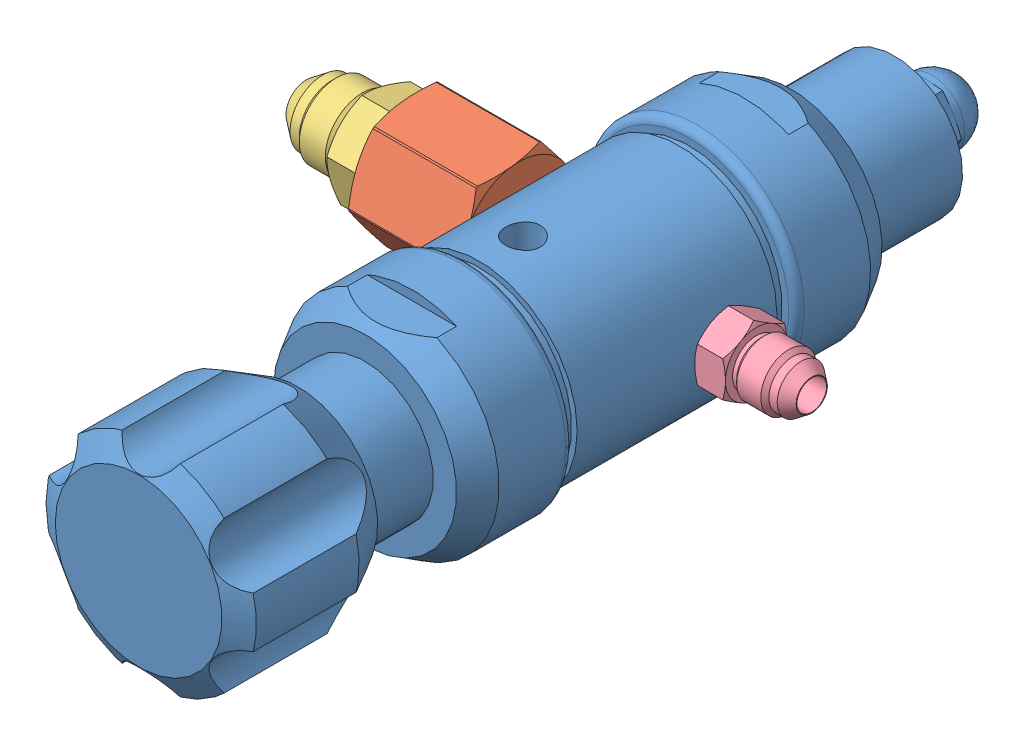
SolidWorks assembly PRV-3 Assembly, configuration Default. Lengths in mm.
Overall size (139.78 55.88 212.09).
4 component instances, 4 part files, 5 mates.
Components (placement in the parent):
- KCY1JPA412A20000_PRT_29-1: KCY1JPA412A20000_PRT_29 [Default] at origin size (56.39 55.88 212.09)
- 51205K317_EXTREME-PRESSURE 316 SS THREADED PIPE FITTING-1: 51205K317_EXTREME-PRESSURE 316 SS THREADED PIPE FITTING [51205K317] at (-34.807 0 86.614) x (-1 0 0) z (0 0.601506 -0.798868) size (44.05 32.74 28.57)
- 0500_OD_JIC_to_0500_NPT-1: 0500_OD_JIC_to_0500_NPT [50715K802] at (-59.826 0 86.614) x (-1 0 0) z (0 -0.969103 0.246658) size (55.21 25.66 22.23)
- 50715K163_TYPE 316 SS 37 DEGREE FLARED TUBE FITTING-1: 50715K163_TYPE 316 SS 37 DEGREE FLARED TUBE FITTING [50715K163] at (29.187 0 86.614) size (36.32 18.33 15.88)
Mates (geometry in assembly coordinates):
- Concentric2: concentric aligned: cone of KCY1JPA412A20000_PRT_29-1 through (-23.853 0 86.614) axis (1 0 0); cylinder of 51205K317_EXTREME-PRESSURE 316 SS THREADED PIPE FITTING-1 through (-13.344 0 86.614) axis (1 0 0) radius 3.556
- Distance2: distance = 2 mm anti-aligned: plane of 51205K317_EXTREME-PRESSURE 316 SS THREADED PIPE FITTING-1 through (-13.344 0 86.614) normal (1 0 0); plane of KCY1JPA412A20000_PRT_29-1 through (-15.344 0 86.614) normal (-1 0 0)
- Concentric3: concentric aligned: circle of 51205K317_EXTREME-PRESSURE 316 SS THREADED PIPE FITTING-1; cone of 0500_OD_JIC_to_0500_NPT-1 through (-56.27 0 86.614) axis (1 0 0)
- Concentric4: concentric aligned: cone of KCY1JPA412A20000_PRT_29-1 through (23.853 0 86.614) axis (-1 0 0); cylinder of 50715K163_TYPE 316 SS 37 DEGREE FLARED TUBE FITTING-1 through (25.25 0 86.614) axis (-1 0 0) radius 3.556
- Tangent1: tangent anti-aligned: cylinder of KCY1JPA412A20000_PRT_29-1 through (0 0 79.502) axis (0 0 1) radius 25.25; plane of 50715K163_TYPE 316 SS 37 DEGREE FLARED TUBE FITTING-1 through (25.25 4.5827 78.6765) normal (-1 0 0)
